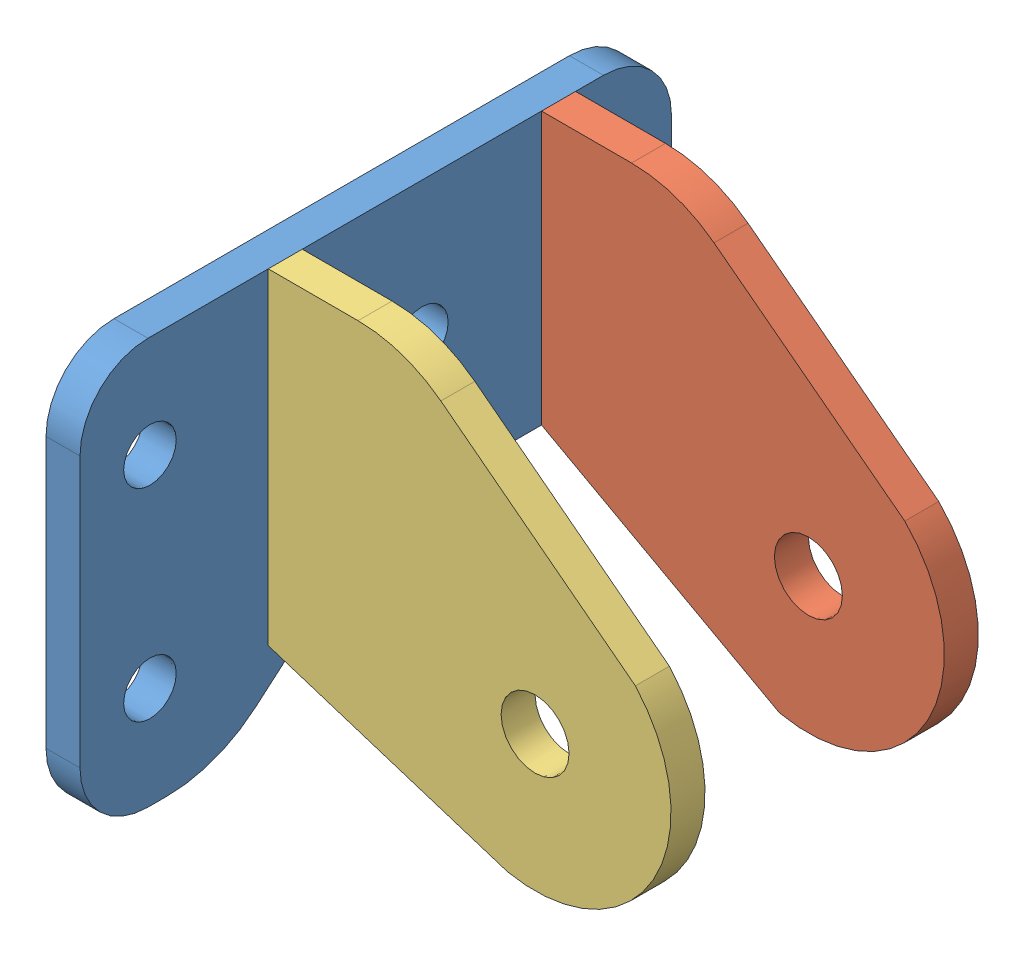
SolidWorks assembly WT-A8###-AA-Front Toe Bracket, configuration Default. Lengths in mm.
Overall size (40.8 37.93 55.25).
3 component instances, 3 part files, 9 mates.
Components (placement in the parent):
- WT-FB-Toe Base Plate-1: WT-FB-Toe Base Plate [Default] at (22.5935 33.4208 28.102) size (3.17 37.93 55.25)
- WT-FB-Toe Bottom Clevis-1: WT-FB-Toe Bottom Clevis [Default] at (-402.1509 50.6365 13.751) size (40.8 37.86 3.17)
- WT-FB-Toe Top Clevis-1: WT-FB-Toe Top Clevis [Default] at (52.058 56.7183 39.278) size (40.8 37.86 3.17)
Mates (geometry in assembly coordinates):
- Coincident16: coincident: plane of WT-FB-Toe Base Plate-1 through (25.7685 25.2365 42.453) normal (0 0 -1); plane of WT-FB-Toe Top Clevis-1 through (50.6923 -12.928 42.453) normal (0 0 1)
- Coincident18: coincident: plane of WT-FB-Toe Base Plate-1 through (25.7685 44.2865 39.278) normal (0 0 1); plane of WT-FB-Toe Top Clevis-1 through (50.6923 -12.928 39.278) normal (0 0 -1)
- Coincident19: coincident: plane of WT-FB-Toe Base Plate-1 through (25.7685 25.4041 51.9175) normal (1 0 0); plane of WT-FB-Toe Top Clevis-1 through (25.7685 12.2333 42.453) normal (-1 0 0)
- Coincident21: coincident: plane of WT-FB-Toe Base Plate-1 through (25.7685 28.4115 13.751) normal (0 0 1); plane of WT-FB-Toe Bottom Clevis-1 through (48.6991 50.6365 13.751) normal (0 0 -1)
- Coincident23: coincident anti-aligned: plane of WT-FB-Toe Base Plate-1 through (25.7685 47.4615 16.926) normal (0 0 -1); plane of WT-FB-Toe Bottom Clevis-1 through (42.3491 50.6365 16.926) normal (0 0 1)
- Coincident26: coincident aligned: plane of WT-FB-Toe Base Plate-1 through (22.5935 25.4041 51.9175) normal (-1 0 0); plane of WT-FB-Toe Bottom Clevis-1 through (22.5935 28.4115 16.926) normal (-1 0 0)
- Coincident27: coincident anti-aligned: plane of WT-FB-Toe Base Plate-1 through (25.7685 28.4115 16.926) normal (0 1 0); plane of WT-FB-Toe Bottom Clevis-1 through (25.7685 28.4115 16.926) normal (0 -1 0)
- Coincident28: coincident anti-aligned: plane of WT-FB-Toe Base Plate-1 through (25.7685 47.4615 16.926) normal (0 0 -1); plane of WT-FB-Toe Bottom Clevis-1 through (50.6923 25.4752 16.926) normal (0 0 1)
- Coincident29: coincident anti-aligned: plane of WT-FB-Toe Base Plate-1 through (25.7685 44.2865 42.453) normal (0 -1 0); plane of WT-FB-Toe Top Clevis-1 through (22.5935 5.8833 42.453) normal (0 1 0)
